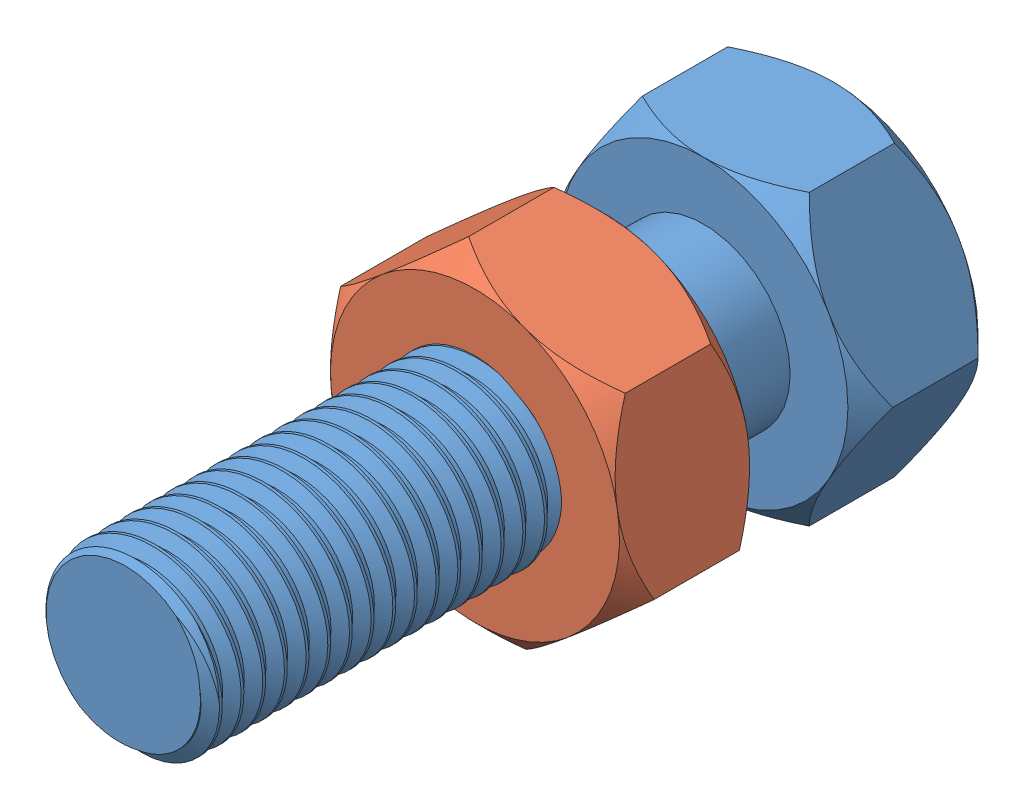
SolidWorks assembly Assem1, configuration Default. Lengths in mm.
Overall size (30.72 27.51 49.58).
2 component instances, 2 part files, 3 mates.
Components (placement in the parent):
- Bolt-1: Bolt [Default] at (-9.0367 49.631 36.4551) size (25.4 20 49.58)
- Nut-1: Nut [Default] at (-9.0367 49.631 52.266) x (-0.939137 0.343543 0) z (0 0 1) size (25.4 20 10.05)
Mates (geometry in assembly coordinates):
- Coincident1: coincident: line of assembly; line of assembly; axis of Bolt-1 through (-9.0367 49.631 35.6223) axis (0 0 -1); axis of Nut-1 through (-9.0367 49.631 46.466) axis (0 0 1)
- Screw1: screw = 1.5 mm: cylinder of assembly; line of assembly; cylinder of Bolt-1 through (-9.0367 49.631 80.9551) axis (0 0 -1) radius 6; axis of Nut-1 through (-9.0367 49.631 51.2989) axis (0 0 1)
- LimitDistance1: limit distance = 6.8109 mm anti-aligned: plane of Nut-1 through (-9.0367 49.631 47.766) normal (0 0 -1); plane of Bolt-1 through (-9.0367 49.631 40.9551) normal (0 0 1)
